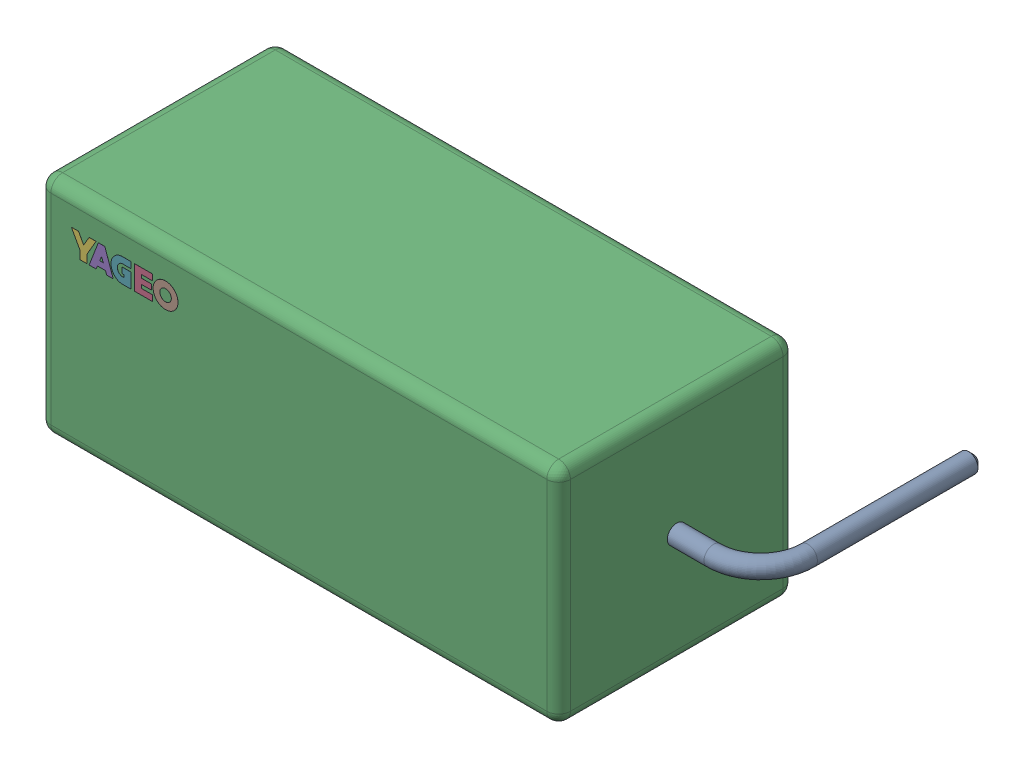
SolidWorks assembly Res_Yageo_SQP500JB-1R2_eec.step, configuration Default. Lengths in mm.
Overall size (29.91 9.5 14).
3 component instances, 3 part files, 0 mates.
Components (placement in the parent):
- 1-6.step-1: 1-6.step [Default] at origin size (29.91 0.8 9.4)
- 2-7.step-1: 2-7.step [Default] at origin size (22 9.5 10)
- Yageo_Logo.step-1: Yageo_Logo.step [Default] at (-8.1443 3.6121 9.991) size (4.52 1.05 0.01)
